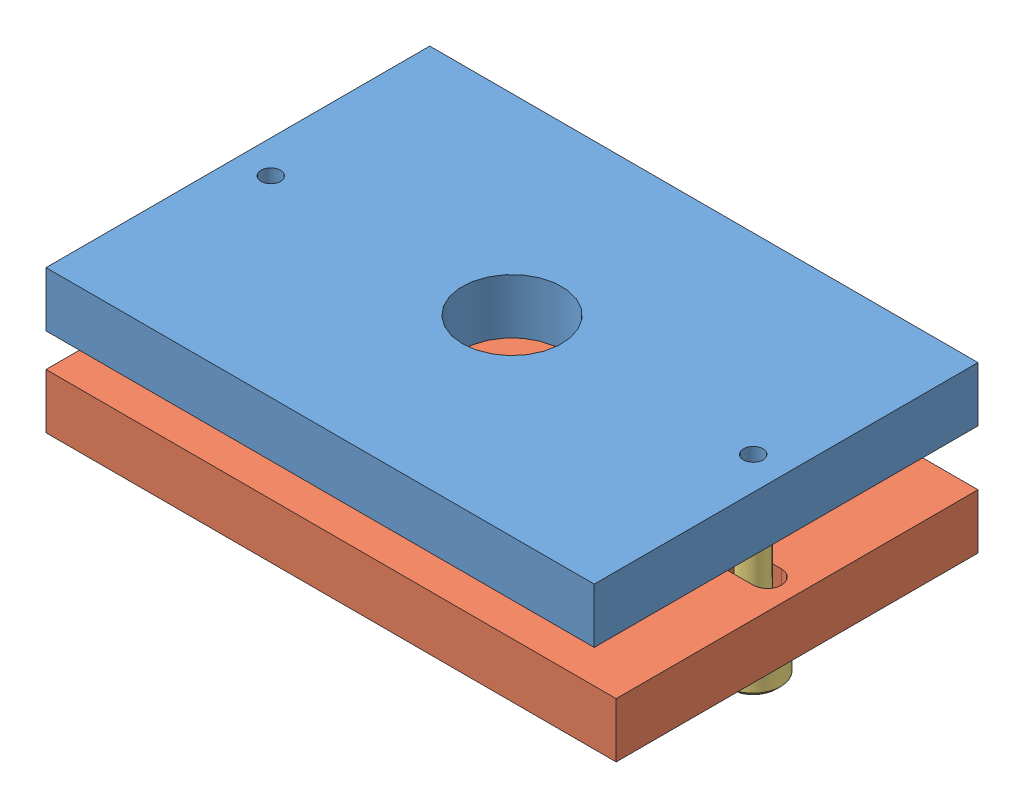
SolidWorks assembly CK tools prototype, configuration Default. Lengths in mm.
Overall size (66.04 22.23 44.45).
4 component instances, 3 part files, 6 mates.
Components (placement in the parent):
- Lid Part A-1: Lid Part A [Default] at (-6.1598 2.8622 -22.3232) size (63.5 6.35 44.45)
- Plate Part B-1: Plate Part B [Default] at (8.3414 -8.6265 -2.0589) size (66.04 6.35 41.91)
- 1-2 in shoulder screw 1-8 dia-1: 1-2 in shoulder screw 1-8 dia [91829A522] at (-29.3472 -9.8378 -3.359) x (1 0 0) z (0 0 -1) size (6.35 20.12 6.35)
- 1-2 in shoulder screw 1-8 dia-2: 1-2 in shoulder screw 1-8 dia [91829A522] at (26.5328 -9.8378 -3.359) x (1 0 0) z (0 0 -1) size (6.35 20.12 6.35)
Mates (geometry in assembly coordinates):
- Concentric1: concentric aligned: circle of Lid Part A-1; circle of 1-2 in shoulder screw 1-8 dia-2
- Concentric2: concentric aligned: circle of Lid Part A-1; circle of 1-2 in shoulder screw 1-8 dia-1
- Coincident1: coincident anti-aligned: plane of Lid Part A-1 through (-33.1572 2.8622 18.866) normal (0 -1 0); plane of 1-2 in shoulder screw 1-8 dia-2 through (26.5328 2.8622 -3.359) normal (0 1 0)
- Coincident2: coincident anti-aligned: plane of Lid Part A-1 through (-33.1572 2.8622 18.866) normal (0 -1 0); plane of 1-2 in shoulder screw 1-8 dia-1 through (-29.3472 2.8622 -3.359) normal (0 1 0)
- Concentric3: concentric anti-aligned: circle of Plate Part B-1; cylinder of 1-2 in shoulder screw 1-8 dia-1 through (-29.3472 2.8622 -3.359) axis (0 -1 0) radius 1.5875
- Concentric4: concentric: cylinder of Plate Part B-1 through (26.5328 0.8985 -3.359) axis (0 1 0) radius 1.632; cylinder of 1-2 in shoulder screw 1-8 dia-2 through (26.5328 2.8622 -3.359) axis (0 -1 0) radius 1.5875
